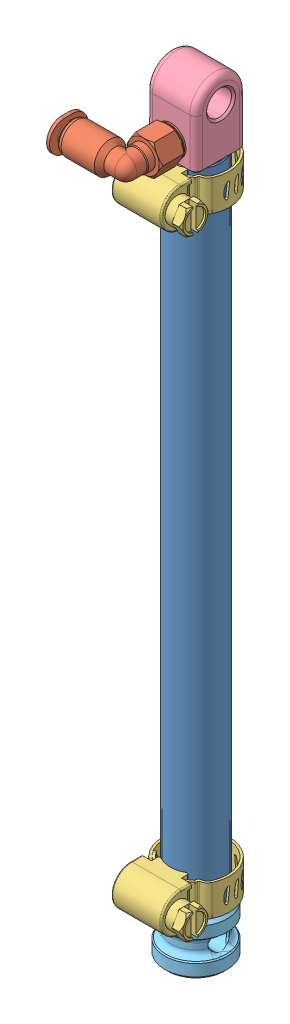
SolidWorks assembly AARL_QR_PN_PA_FR_WR_EX-Extensor, configuration Default. Lengths in mm.
Overall size (26.6 196.85 31.28).
6 component instances, 5 part files, 15 mates.
Components (placement in the parent):
- AARL_QR_PN_PA_FR_WR_EX_001-1: AARL_QR_PN_PA_FR_WR_EX_001 [Resting] at origin size (12.7 165.1 12.7)
- AARL_Puppy_18_02_57_010-QSML-M3-4-1: AARL_Puppy_18_02_57_010-QSML-M3-4 [Default] at (0 87.3125 17.85) x (-1 0 0) z (0 0 -1) size (20.32 8 18.9)
- AARL_Puppy_18_02_57_011-5388K140_Hose-Clamp-1: AARL_Puppy_18_02_57_011-5388K140_Hose-Clamp [5388K14] at (0 -77.597 0) x (1 0 0) z (0 -1 0) size (19.43 23.71 9.91)
- AARL_Puppy_18_02_57_011-5388K140_Hose-Clamp-2: AARL_Puppy_18_02_57_011-5388K140_Hose-Clamp [5388K14] at (0 77.597 0) x (1 0 0) z (0 -1 0) size (19.43 23.71 9.91)
- AARL_QR_PN_EP_001-1: AARL_QR_PN_EP_001 [Default] at (0 95.25 0) x (0 0 1) z (-1 0 0) size (12.7 31.75 12.7)
- AARL_QR_PN_EP_002-1: AARL_QR_PN_EP_002 [Default] at (0 -82.55 0) x (-1 0 0) z (0 0 1) size (15.88 25.4 15.88)
Mates (geometry in assembly coordinates):
- Concentric1: concentric aligned: cylinder of AARL_QR_PN_PA_FR_WR_EX_001-1 through (0 11.6086 0) axis (0 1 0) radius 4.7625; cylinder of AARL_QR_PN_EP_001-1 through (0 104.794 0) axis (0 1 0) radius 4.3656
- Coincident1: coincident anti-aligned: plane of AARL_QR_PN_PA_FR_WR_EX_001-1 through (4.7625 82.55 0) normal (0 1 0); plane of AARL_QR_PN_EP_001-1 through (-6.35 82.55 -6.35) normal (0 -1 0)
- Parallel1: parallel aligned: plane of AARL_QR_PN_EP_001-1 through (-6.35 82.55 6.35) normal (0 0 1)
- Concentric2: concentric aligned: cylinder of AARL_Puppy_18_02_57_010-QSML-M3-4-1 through (0 87.3125 6.35) axis (0 0 1) radius 1.5; cylinder of AARL_QR_PN_EP_001-1 through (0 87.3125 6.35) axis (0 0 1) radius 2.0193
- Coincident3: coincident anti-aligned: plane of AARL_Puppy_18_02_57_010-QSML-M3-4-1 through (0 87.3125 6.35) normal (0 0 -1); plane of AARL_QR_PN_EP_001-1 through (-6.35 82.55 6.35) normal (0 0 1)
- Parallel2: parallel aligned: plane of AARL_Puppy_18_02_57_010-QSML-M3-4-1 through (2.3094 83.3125 13.4056) normal (0 -1 0); plane of AARL_QR_PN_EP_001-1 through (-6.35 82.55 -6.35) normal (0 -1 0)
- Concentric3: concentric anti-aligned: cylinder of AARL_QR_PN_PA_FR_WR_EX_001-1 through (0 11.6086 0) axis (0 1 0) radius 4.7625; cylinder of AARL_QR_PN_EP_002-1 through (0 -90.2877 0) axis (0 -1 0) radius 4.3656
- Parallel3: parallel anti-aligned: cylinder of AARL_QR_PN_EP_001-1 through (-6.35 95.25 0) axis (1 0 0) radius 3.175; cylinder of AARL_QR_PN_EP_002-1 through (7.9375 -88.9 0) axis (-1 0 0) radius 2.3813
- Coincident5: coincident anti-aligned: plane of AARL_QR_PN_PA_FR_WR_EX_001-1 through (6.35 -82.55 0) normal (0 -1 0); plane of AARL_QR_PN_EP_002-1 through (-4.3656 -82.55 0) normal (0 1 0)
- Concentric5: concentric aligned: cylinder of AARL_QR_PN_PA_FR_WR_EX_001-1 through (0 11.6086 0) axis (0 1 0) radius 6.35; cylinder of AARL_Puppy_18_02_57_011-5388K140_Hose-Clamp-2 through (0 73.6283 0) axis (0 1 0) radius 7.9375
- Coincident6: coincident aligned: plane of AARL_Puppy_18_02_57_011-5388K140_Hose-Clamp-2 through (6.35 77.597 10.2337) normal (1 0 0); plane of AARL_QR_PN_EP_001-1 through (6.35 95.25 0) normal (1 0 0)
- Coincident7: coincident anti-aligned: plane of AARL_Puppy_18_02_57_011-5388K140_Hose-Clamp-2 through (0 82.55 0) normal (0 1 0); plane of AARL_QR_PN_EP_001-1 through (-6.35 82.55 -6.35) normal (0 -1 0)
- Concentric6: concentric aligned: cylinder of AARL_QR_PN_PA_FR_WR_EX_001-1 through (0 11.6086 0) axis (0 1 0) radius 6.35; cylinder of AARL_Puppy_18_02_57_011-5388K140_Hose-Clamp-1 through (0 -81.5658 0) axis (0 1 0) radius 7.9375
- Coincident8: coincident aligned: plane of AARL_Puppy_18_02_57_011-5388K140_Hose-Clamp-1 through (6.35 -77.597 10.2337) normal (1 0 0); plane of AARL_Puppy_18_02_57_011-5388K140_Hose-Clamp-2 through (6.35 77.597 10.2337) normal (1 0 0)
- Coincident9: coincident anti-aligned: plane of AARL_Puppy_18_02_57_011-5388K140_Hose-Clamp-1 through (0 -82.55 0) normal (0 -1 0); plane of AARL_QR_PN_EP_002-1 through (-4.3656 -82.55 0) normal (0 1 0)
